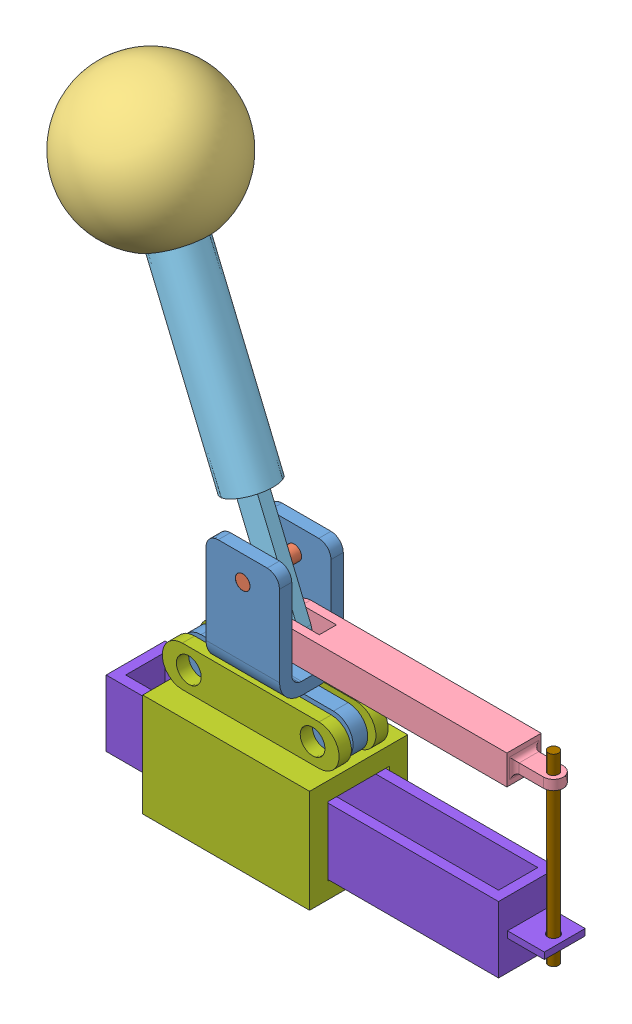
SolidWorks assembly Upper_Assembly, configuration Default. Lengths in mm.
Overall size (214.69 258.14 74.45).
10 component instances, 9 part files, 17 mates.
Components (placement in the parent):
- Box_Pivot-1: Box_Pivot [Default] at (11.9261 53.6915 54.2812) size (70 63 26)
- Big Post-1: Big Post [Default] at (11.9261 68.2515 41.2812) x (0.772904 -0.634523 0) z (0 0 1) size (5.9 5.9 26)
- Handle-1: Handle [Default] at (-38.5518 189.1357 54.2812) x (-0.259356 -0.1083 -0.95969) z (0.885583 0.369795 -0.28106) size (60 56 60)
- Link-1: Link [Default] at (113.6327 49.7959 54.2812) size (116 12 14)
- Post Handle-1: Post Handle [Default] at (-13.1201 128.2322 54.2812) x (-0.385328 0.92278 0) z (0 0 1) size (140 20 20)
- Small Post-1: Small Post [Default] at (19.6327 49.7959 47.2812) x (0.979703 -0.200456 0) z (0 0 1) size (5.9 5.9 14)
- Lower_Assembly-2: Lower_Assembly [Default] at (-2.8058 -28.6398 47.4605) x (-1 0 0) z (0 0 -1) size (175 58.45 40) (flexible)
  - Lower_Base-1: Lower_Base [Default] at (-14.973 51.8913 -6.8208) size (72.14 58.45 40)
  - cartridge-1: cartridge [Default] at (-118.0354 8.2927 5.1792) x (0 0 -1) z (1 0 0) size (24 27 175)
- Long Post-1: Long Post [Default] at (129.3797 -15.6895 43.3286) x (-0.306631 0 0.951829) z (0 -1 0) size (4.16 4.16 75)
Mates (geometry in assembly coordinates):
- Concentric1: concentric anti-aligned: cylinder of Box_Pivot-1 through (11.9261 68.2515 41.2812) axis (0 0 1) radius 3; cylinder of Big Post-1 through (11.9261 68.2515 67.2812) axis (0 0 -1) radius 2.95
- Coincident1: coincident aligned: plane of Box_Pivot-1 through (26.9261 78.2515 67.2812) normal (0 0 1); plane of Big Post-1 through (11.9261 68.2515 67.2812) normal (0 0 1)
- Concentric2: concentric aligned: cylinder of Big Post-1 through (11.9261 68.2515 67.2812) axis (0 0 -1) radius 2.95; cylinder of Post Handle-1 through (11.9261 68.2515 56.7812) axis (0 0 -1) radius 3
- Width1: width anti-aligned: plane of Box_Pivot-1 through (26.9261 40.2515 46.2812) normal (0 0 1); plane of Post Handle-1 through (26.9261 78.2515 62.2812) normal (0 0 -1); plane of Box_Pivot-1 through (19.6327 49.7959 51.7812) normal (0 0 -1); plane of Post Handle-1 through (19.6327 49.7959 56.7812) normal (0 0 1)
- Concentric3: concentric aligned: cylinder of Handle-1 through (-33.1572 176.2168 54.2812) axis (0.385328 -0.92278 0) radius 6; cylinder of Post Handle-1 through (-32.3865 174.3712 54.2812) axis (0.385328 -0.92278 0) radius 6
- Coincident3: coincident anti-aligned: plane of Handle-1 through (-28.5333 165.1434 54.2812) normal (0.385328 -0.92278 0); plane of Post Handle-1 through (-28.5333 165.1434 54.2812) normal (-0.385328 0.92278 0)
- Concentric4: concentric aligned: cylinder of Link-1 through (19.6327 49.7959 61.2812) axis (0 0 -1) radius 3; cylinder of Post Handle-1 through (19.6327 49.7959 56.7812) axis (0 0 -1) radius 3
- Width2: width anti-aligned: plane of Link-1 through (13.6327 43.7959 50.7812) normal (0 0 1); plane of Post Handle-1 through (33.6327 43.7959 57.7812) normal (0 0 -1); plane of Link-1 through (19.6327 49.7959 51.7812) normal (0 0 -1); plane of Post Handle-1 through (19.6327 49.7959 56.7812) normal (0 0 1)
- Concentric5: concentric aligned: cylinder of Post Handle-1 through (19.6327 49.7959 56.7812) axis (0 0 -1) radius 3; cylinder of Small Post-1 through (19.6327 49.7959 61.2812) axis (0 0 -1) radius 2.95
- Width3: width anti-aligned: plane of Small Post-1 through (19.6327 49.7959 61.2812) normal (0 0 1); plane of Link-1 through (19.6327 49.7959 47.2812) normal (0 0 -1); plane of Small Post-1 through (19.6327 49.7959 47.2812) normal (0 0 -1); plane of Link-1 through (19.6327 49.7959 61.2812) normal (0 0 1)
- Parallel1: parallel aligned: plane of Box_Pivot-1 through (26.9261 36.2515 58.2812) normal (0 1 0); plane of Link-1 through (113.6327 55.7959 61.2812) normal (0 1 0)
- Width4: width aligned: plane of Lower_Assembly-2/Lower_Base-1 through (12.1672 23.2515 49.2812) normal (0 0 1); plane of Box_Pivot-1 through (12.1672 23.2515 59.2812) normal (0 0 -1); plane of Lower_Assembly-2/Lower_Base-1 through (-15.0739 23.2515 57.2812) normal (0 0 1); plane of Box_Pivot-1 through (-15.0739 23.2515 51.2812) normal (0 0 -1)
- Concentric6: concentric anti-aligned: circle of Box_Pivot-1; circle of Lower_Assembly-2/Lower_Base-1
- Parallel2: parallel aligned: plane of Box_Pivot-1 through (-15.0739 31.2515 57.2812) normal (0 1 0); plane of Lower_Assembly-2/Lower_Base-1 through (40.0272 31.4627 44.2812) normal (0 1 0)
- Concentric7: concentric aligned: circle of Link-1; cylinder of Long Post-1 through (125.6327 59.3105 54.2812) axis (0 -1 0) radius 2.0801
- Width5: width anti-aligned: plane of Link-1 through (129.6327 51.7959 58.2812) normal (0 1 0); plane of Long Post-1 through (130.2296 -8.1749 45.9533) normal (0 -1 0); plane of Lower_Assembly-2/cartridge-1 through (125.6327 -15.6895 54.2812) normal (0 -1 0); plane of Long Post-1 through (125.6327 59.3105 54.2812) normal (0 1 0)
- Concentric8: concentric anti-aligned: circle of Lower_Assembly-2/cartridge-1; cylinder of Long Post-1 through (125.6327 59.3105 54.2812) axis (0 -1 0) radius 2.0801
